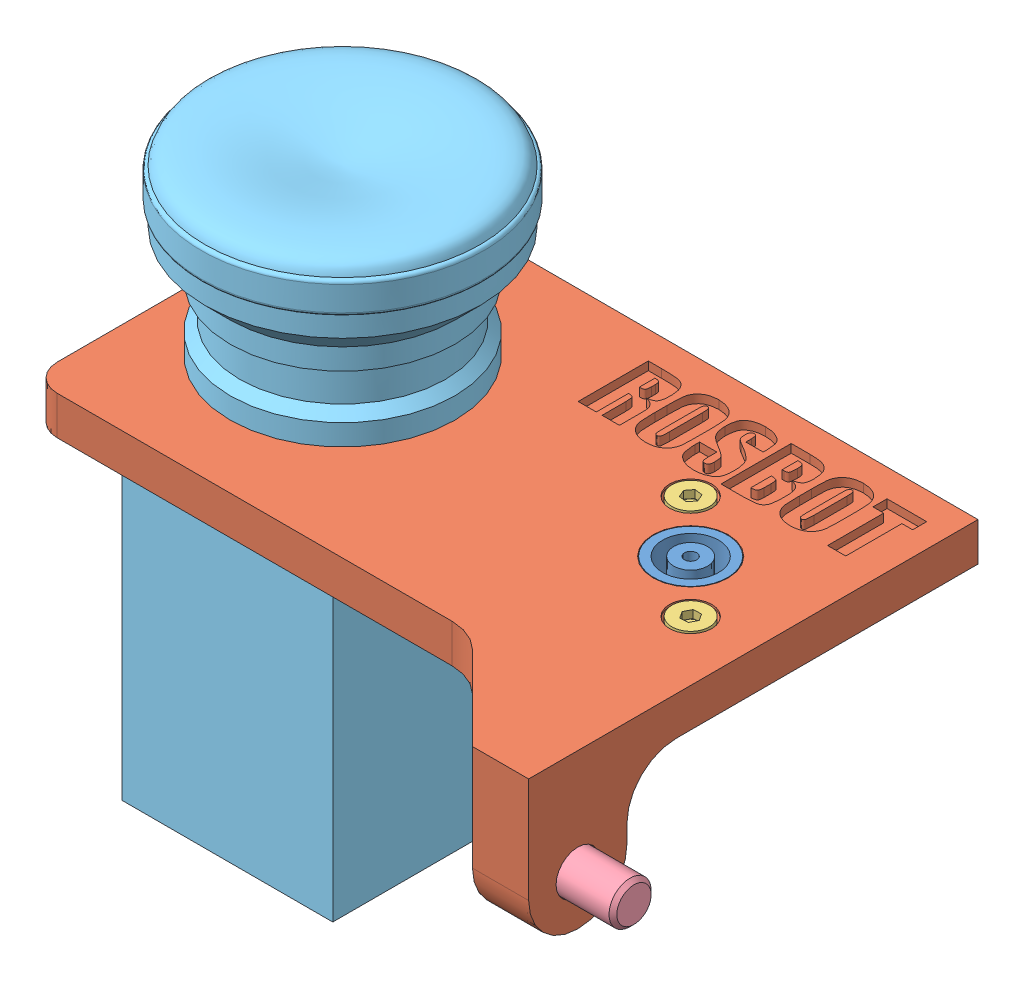
SolidWorks assembly charge-port, configuration Default. Lengths in mm.
Overall size (107 79.94 72).
7 component instances, 5 part files, 15 mates.
Components (placement in the parent):
- charge-port-1: charge-port [Default] at (0 -6.1 0) x (0.707107 0 0.707107) z (-0.707107 0 0.707107) size (31 14.45 15)
- charge-port-mount-1: charge-port-mount [Visual] x (1 0 0) z (0 1 0) size (99 64 22)
- socket countersunk head screw_am-1: socket countersunk head screw_am [B18.3.5M - 3 x 0.5 x 8 Socket FCHS  -- 8N] at (-7.4246 2.56 -7.4246) x (0 -1 0) z (-0.128943 0 0.991652) size (8 5.35 5.35)
- socket countersunk head screw_am-2: socket countersunk head screw_am [B18.3.5M - 3 x 0.5 x 8 Socket FCHS  -- 8N] at (7.4246 2.56 7.4246) x (0 -1 0) z (0.051179 0 0.998689) size (8 5.35 5.35)
- socket head cap screw_am-1: socket head cap screw_am [B18.3.1M - 6 x 1.0 x 12 Hex SHCS -- 12NHX] at (5.9246 -12.5 32) x (1 0 0) z (0 0.816639 0.577149) size (18 10 10)
- socket head cap screw_am-2: socket head cap screw_am [B18.3.1M - 6 x 1.0 x 12 Hex SHCS -- 12NHX] at (-76.0754 -12.5 -15) x (0 0 -1) z (-0.996731 0.080786 0) size (18 10 10)
- e-stop-1: e-stop [Default] at (-49.5754 -10.5 0) x (-1 0 0) z (0 0 -1) size (40.2 79.94 44.5)
Mates (geometry in assembly coordinates):
- InPlace1: in place: plane of assembly through (0 6.1 0) normal (0 1 0); plane of ? through (0 6.1 0) normal (0 1 0); moOrthogonalPlaneRef_w of assembly through (0 6.1 0) normal (0 1 0); plane of ? through (0 6.1 0) normal (0 0 -1); plane of assembly through (0 6.1 0) normal (0 1 0); plane of ? through (0 6.1 0) normal (1 0 0); plane of charge-port-1 through (0 0 0) normal (0 1 0); unknown of ?
- Coincident1: coincident aligned: plane of charge-port-1; plane of ?
- Coincident2: coincident aligned: moOrthogonalPlaneRef_w of charge-port-1; plane of Part3^Assem1-1 through (0 6.1 0) normal (0 0 -1)
- Coincident3: coincident anti-aligned: moOrthogonalPlaneRef_w of charge-port-1; plane of Part3^Assem1-1 through (0 6.1 0) normal (1 0 0)
- Coincident4: coincident anti-aligned: plane of charge-port-1 through (0 0 0) normal (0 1 0); plane of charge-port-mount-1 through (0 0 0) normal (0 -1 0)
- Concentric1: concentric aligned: cylinder of charge-port-1 through (-7.4246 0 -7.4246) axis (0 -1 0) radius 1.5; cylinder of charge-port-mount-1 through (-7.4246 2.5 -7.4246) axis (0 -1 0) radius 1.6
- Concentric3: concentric aligned: cylinder of charge-port-1 through (7.4246 0 7.4246) axis (0 -1 0) radius 1.5; cylinder of charge-port-mount-1 through (7.4246 2.5 7.4246) axis (0 -1 0) radius 1.6
- Coincident5: coincident aligned: cone of charge-port-mount-1 through (-7.4246 2.2 -7.4246) axis (0 -1 0); cone of socket countersunk head screw_am-1 through (-7.4246 1.875 -7.4246) axis (0 -1 0)
- Coincident6: coincident aligned: cone of charge-port-mount-1 through (7.4246 2.2 7.4246) axis (0 -1 0); cone of socket countersunk head screw_am-2 through (7.4246 1.875 7.4246) axis (0 -1 0)
- Concentric4: concentric aligned: cylinder of charge-port-mount-1 through (15.9256 -12.5 32) axis (-1 0 0) radius 3.1; cylinder of socket head cap screw_am-1 through (-25.8254 -12.5 32) axis (-1 0 0) radius 5
- Concentric5: concentric aligned: cylinder of charge-port-mount-1 through (-76.0754 -12.5 -21) axis (0 0 1) radius 5; cylinder of socket head cap screw_am-2 through (-76.0754 -12.5 16.75) axis (0 0 1) radius 5
- Coincident8: coincident anti-aligned: plane of charge-port-mount-1 through (-76.0754 -12.5 -21) normal (0 0 1); plane of socket head cap screw_am-2 through (-76.4793 -17.4837 -21) normal (0 0 -1)
- Coincident9: coincident anti-aligned: plane of charge-port-mount-1 through (11.9246 -12.5 32) normal (-1 0 0); plane of socket head cap screw_am-1 through (11.9246 -9.6143 27.9168) normal (1 0 0)
- Coincident10: coincident anti-aligned: plane of charge-port-mount-1 through (0 2.5 0) normal (0 1 0); plane of e-stop-1 through (-38.5754 2.5 0) normal (0 -1 0)
- Concentric6: concentric anti-aligned: cylinder of charge-port-mount-1 through (-49.5754 2.5 0) axis (0 -1 0) radius 11; cylinder of e-stop-1 through (-49.5754 21.801 0) axis (0 1 0) radius 11
